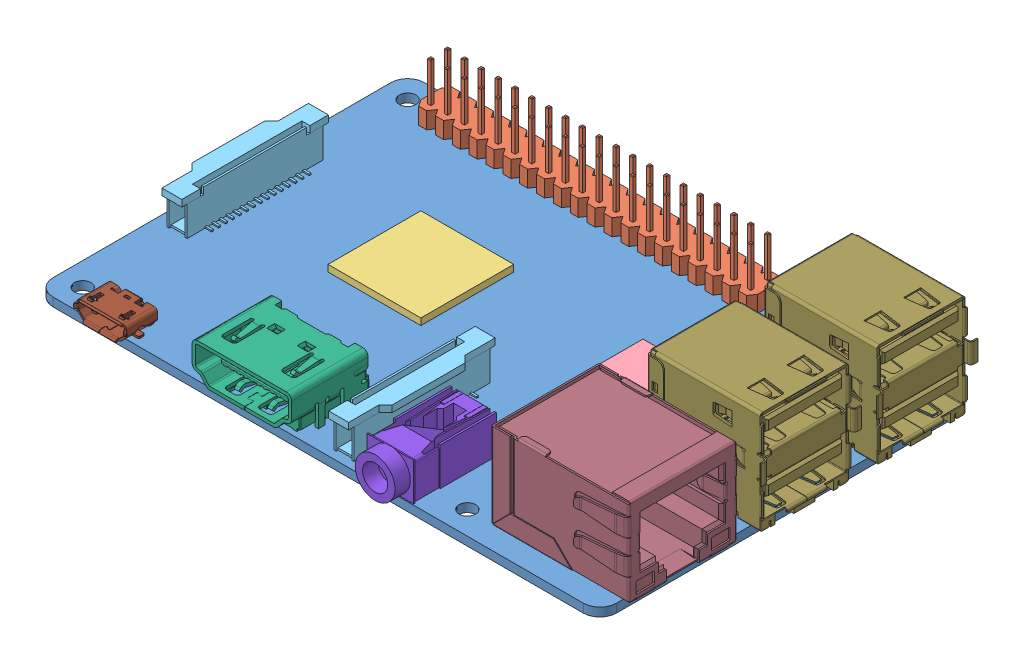
SolidWorks assembly RaspberryPi2 model B SW, configuration Default. Lengths in mm.
Overall size (89.62 18.75 58.3).
15 component instances, 13 part files, 43 mates.
Components (placement in the parent):
- Mainboard2-1: Mainboard2 [Default] at origin size (85 1.3 56)
- GPIO-1: GPIO [Default] at (-11.37 0 -24.5) x (0 0 1) z (-1 0 0) size (5 11.5 50.8)
- Processor-1: Processor [Default] at (-15.5 0 -3) x (0 0 1) z (-1 0 0) size (14 1 14)
- GPU-1: GPU [Default] at (15.25 0 -5.75) x (0 0 1) z (-1 0 0) size (9.1 1 9.1)
- CameraAssembly-4: CameraAssembly [Default] at (10.0885 -2.9159 16.55) x (-1 0 0) z (0 0 -1) size (5 5.5 22.1)
- CameraAssembly-3: CameraAssembly [Default] at (-46.3885 -2.9159 0) size (5 5.5 22.1)
- hdmi-1: hdmi [Default] at (-10.2 0.27 29.3) size (15.14 8.38 12.15)
- RAM-1: RAM [Default] at (0.5 -2.3 -6) x (0 0 1) z (-1 0 0) size (12 1 12)
- Audio-1: Audio [Default] at (10.9 0.15 21.75) size (7 6 14.8)
- MicroSDSocket-1: MicroSDSocket [Default] at (-34.5 -1.3 -0.7) x (0 0 -1) z (-1 0 0) size (13 1.3 14)
- MicroSD-1: MicroSD [Default] at (-37 -2.3 0.1) x (0 0 1) z (-1 0 0) size (11 1 15)
- micro USB2-1: micro USB2 [Default] at (-17.2704 -5.0969 44.9026) size (7.99 2.94 5.43)
- usb double-1: usb double [Default] at (30.38 -0.09 -18.85) x (0 0 -1) z (1 0 0) size (15.6 18.75 17.92)
- usb double-2: usb double [Default] at (30.38 -0.09 -1.25) x (0 0 -1) z (1 0 0) size (15.6 18.75 17.92)
- RJ45-LED-1: RJ45-LED [Default] at (34.11 7.4 17.348) x (1 0 0) z (0 -1 0) size (20.75 17.99 14.09)
Mates (geometry in assembly coordinates):
- Coincidente19: coordinate: point of Mainboard2-1; point of assembly
- Distanza16: distance = 2.3 mm aligned: plane of Audio-1 through (10.9 6 30.3) normal (0 0 1); plane of Mainboard2-1 through (-40 -1.3 28) normal (0 0 1)
- Distanza17: distance = 28.1 mm aligned: plane of Audio-1 through (14.4 0.15 28) normal (1 0 0); plane of Mainboard2-1 through (42.5 -1.3 25.5) normal (1 0 0)
- Distanza20: distance = 6.5 mm aligned: plane of hdmi-1 through (-4.6 6.5 17.85) normal (0 1 0); plane of Mainboard2-1 through (40 0 25.5) normal (0 1 0)
- Distanza27: distance = 0.1 mm anti-aligned: plane of MicroSD-1 through (-37.1747 -2.3 0.1936) normal (0 -1 0); plane of MicroSDSocket-1 through (-34.5 -2.4 -0.7) normal (0 1 0)
- Coincidente39: coincident anti-aligned: plane of MicroSDSocket-1 through (-27.5 -1.3 5.6) normal (0 0 -1); plane of MicroSD-1 through (-44.5 -2.3 5.6) normal (0 0 1)
- Distanza28: distance = 3 mm aligned: plane of MicroSD-1 through (-44.5 -2.3 -5.4) normal (-1 0 0); plane of MicroSDSocket-1 through (-41.5 -1.3 5.8) normal (-1 0 0)
- Coincidente41: coincident anti-aligned: plane of Mainboard2-1 through (40 -1.3 25.5) normal (0 -1 0); plane of MicroSDSocket-1 through (-34.5 -1.3 -0.7) normal (0 1 0)
- Distanza29: distance = 1 mm aligned: plane of MicroSDSocket-1 through (-41.5 -1.3 5.8) normal (-1 0 0); plane of Mainboard2-1 through (-42.5 -1.3 -25.5) normal (-1 0 0)
- Distanza30: distance = 20.8 mm aligned: plane of MicroSDSocket-1 through (-41.5 -1.3 -7.2) normal (0 0 -1); plane of Mainboard2-1 through (40 -1.3 -28) normal (0 0 -1)
- Coincidente44: coincident anti-aligned: plane of Mainboard2-1 through (40 0 25.5) normal (0 1 0); plane of GPIO-1 through (-11.37 0 -24.5) normal (0 -1 0)
- Distanza31: distance = 7 mm aligned: plane of GPIO-1 through (-35.5 0 -26) normal (-1 0 0); plane of Mainboard2-1 through (-42.5 -1.3 -25.5) normal (-1 0 0)
- Distanza32: distance = 1 mm aligned: plane of GPIO-1 through (-33.63 0 -27) normal (0 0 -1); plane of Mainboard2-1 through (40 -1.3 -28) normal (0 0 -1)
- Coincidente47: coincident anti-aligned: plane of Mainboard2-1 through (40 0 25.5) normal (0 1 0); plane of Processor-1 through (-15.5 0 -3) normal (0 -1 0)
- Distanza33: distance = 18 mm aligned: plane of Processor-1 through (-8.5 0 -10) normal (0 0 -1); plane of Mainboard2-1 through (40 -1.3 -28) normal (0 0 -1)
- Distanza34: distance = 20 mm aligned: plane of Processor-1 through (-22.5 0 -10) normal (-1 0 0); plane of Mainboard2-1 through (-42.5 -1.3 -25.5) normal (-1 0 0)
- Coincidente50: coincident anti-aligned: plane of Mainboard2-1 through (40 -1.3 25.5) normal (0 -1 0); plane of RAM-1 through (0.5 -1.3 -6) normal (0 1 0)
- Distanza35: distance = 16 mm aligned: plane of RAM-1 through (6.5 -2.3 -12) normal (0 0 -1); plane of Mainboard2-1 through (40 -1.3 -28) normal (0 0 -1)
- Distanza36: distance = 37 mm aligned: plane of RAM-1 through (-5.5 -2.3 -12) normal (-1 0 0); plane of Mainboard2-1 through (-42.5 -1.3 -25.5) normal (-1 0 0)
- Coincidente53: coincident anti-aligned: plane of Mainboard2-1 through (40 0 25.5) normal (0 1 0); plane of GPU-1 through (15.25 0 -5.75) normal (0 -1 0)
- Distanza37: distance = 18 mm aligned: plane of GPU-1 through (19.5 0 -10) normal (0 0 -1); plane of Mainboard2-1 through (40 -1.3 -28) normal (0 0 -1)
- Distanza38: distance = 23 mm aligned: plane of GPU-1 through (19.5 0 -1.5) normal (1 0 0); plane of Mainboard2-1 through (42.5 -1.3 25.5) normal (1 0 0)
- Distanza39: distance = 1.3 mm aligned: plane of hdmi-1 through (-28.801 6 29.3) normal (0 0 1); plane of Mainboard2-1 through (-40 -1.3 28) normal (0 0 1)
- Distanza40: distance = 24.8 mm aligned: plane of hdmi-1 through (-17.7 18.8639 17.85) normal (-1 0 0); plane of Mainboard2-1 through (-42.5 -1.3 -25.5) normal (-1 0 0)
- Tangente2: tangent anti-aligned: plane of Mainboard2-1 through (40 0 25.5) normal (0 1 0); cylinder of Audio-1 through (10.9 3 29.15) axis (0 0 -1) radius 3
- Distanza43: distance = 2.6 mm anti-aligned: plane of micro USB2-1 through (-34.95 2.6 24.1941) normal (0 -1 0); plane of Mainboard2-1 through (40 0 25.5) normal (0 1 0)
- Distanza44: distance = 1.3 mm anti-aligned: cylinder of micro USB2-1 through (-29.25 0.0937 29.31) axis (-1 0 0) radius 0.01; plane of Mainboard2-1 through (-40 -1.3 28) normal (0 0 1)
- Distanza45: distance = 7 mm anti-aligned: plane of micro USB2-1 through (-35.5 1.3036 24.1941) normal (1 0 0); plane of Mainboard2-1 through (-42.5 -1.3 -25.5) normal (-1 0 0)
- Distanza46: distance = 15.5 mm aligned: plane of usb double-1 through (33.3225 15.5 -40.1817) normal (0 1 0); plane of Mainboard2-1 through (40 0 25.5) normal (0 1 0)
- Coincidente61: coincident aligned: plane of usb double-1 through (33.3225 15.5 -40.1817) normal (0 1 0); plane of usb double-2 through (33.3225 15.5 -22.5817) normal (0 1 0)
- Coincidente63: coincident aligned: plane of usb double-1 through (44.5 -0.09 -18.85) normal (1 0 0); plane of usb double-2 through (44.5 -0.09 -1.25) normal (1 0 0)
- Distanza47: distance = 2.5 mm aligned: plane of usb double-1 through (33.3225 0.4896 -25.5) normal (0 0 -1); plane of Mainboard2-1 through (40 -1.3 -28) normal (0 0 -1)
- Distanza48: distance = 4.3 mm anti-aligned: plane of usb double-2 through (33.3225 0.4896 -7.9) normal (0 0 -1); plane of usb double-1 through (33.3225 43.1529 -12.2) normal (0 0 1)
- Distanza49: distance = 14 mm aligned: plane of RJ45-LED-1 through (44.36 14 25.248) normal (0 1 0); plane of Mainboard2-1 through (40 0 25.5) normal (0 1 0)
- Distanza50: distance = 2 mm aligned: plane of usb double-2 through (44.5 -0.09 -1.25) normal (1 0 0); plane of Mainboard2-1 through (42.5 -1.3 25.5) normal (1 0 0)
- Coincidente68: coincident aligned: plane of usb double-2 through (44.36 -0.09 -1.25) normal (1 0 0); plane of RJ45-LED-1 through (44.36 0.8 25.248) normal (1 0 0)
- Distanza51: distance = 2.5 mm aligned: plane of RJ45-LED-1 through (34.11 7.4 25.5) normal (0 0 1); plane of Mainboard2-1 through (-40 -1.3 28) normal (0 0 1)
- Distanza52: distance = 3.2 mm anti-aligned: plane of Audio-1 through (7.4 0.15 15.5) normal (-1 0 0); plane of CameraAssembly-4 through (4.2 0 26.8) normal (1 0 0)
- Distanza53: distance = 1.2 mm aligned: plane of CameraAssembly-4 through (1.2 0 26.8) normal (0 0 1); plane of Mainboard2-1 through (-40 -1.3 28) normal (0 0 1)
- Coincidente72: coincident anti-aligned: plane of Mainboard2-1 through (40 0 25.5) normal (0 1 0); plane of CameraAssembly-4 through (2.7 0 16.55) normal (0 -1 0)
- Distanza54: distance = 2 mm aligned: plane of CameraAssembly-3 through (-40.5 0 -10.25) normal (-1 0 0); plane of Mainboard2-1 through (-42.5 -1.3 -25.5) normal (-1 0 0)
- Distanza55: distance = 17.75 mm: plane of CameraAssembly-3 through (-40.5 0 10.25) normal (0 0 1); line of Mainboard2-1 through (-40 0 28) axis (1 0 0)
- Coincidente75: coincident anti-aligned: plane of Mainboard2-1 through (40 0 25.5) normal (0 1 0); plane of CameraAssembly-3 through (-39 0 0) normal (0 -1 0)
